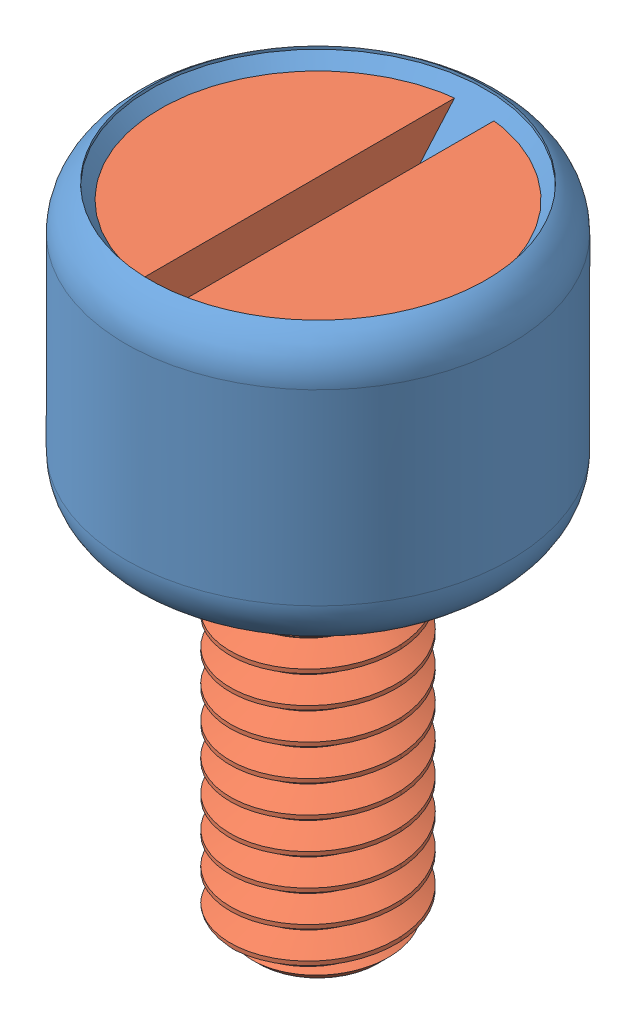
SolidWorks assembly Faux Dzus Stud, configuration Default. Lengths in mm.
Overall size (9.65 16.56 9.65).
2 component instances, 2 part files, 6 mates.
Components (placement in the parent):
- Faux Dzus Stud-1: Faux Dzus Stud [Default] at (0 5.4356 0) x (0 -1 0) z (0 0 1) size (7.05 9.65 9.65)
- 90275A196 - FHS, 82 CSK, 8-32 X .625, STEEL, ZINC-1: 90275A196 - FHS, 82 CSK, 8-32 X .625, STEEL, ZINC [90275A196] at (0 4.1528 0) x (0 0 1) z (0 1 0) size (7.86 7.92 16.2)
Mates (geometry in assembly coordinates):
- Concentric1: concentric aligned: cylinder of Faux Dzus Stud-1 through (0 7.239 0) axis (0 1 0) radius 2.4574
- Coincident1: coincident aligned: plane of Faux Dzus Stud-1 through (0 5.4356 0) normal (1 0 0); plane of assembly through (0 0 0) normal (1 0 0)
- Coincident2: coincident anti-aligned: plane of Faux Dzus Stud-1 through (-4.7498 0 -4.7498) normal (0 -1 0); plane of assembly through (0 0 0) normal (0 1 0)
- Concentric3: concentric aligned: cone of Faux Dzus Stud-1 through (0 6.985 0) axis (0 -1 0); cone of 90275A196 - FHS, 82 CSK, 8-32 X .625, STEEL, ZINC-1 through (0 6.6928 0) axis (0 -1 0)
- Coincident3: coincident aligned: cone of Faux Dzus Stud-1 through (0 6.985 0) axis (0 -1 0); cone of 90275A196 - FHS, 82 CSK, 8-32 X .625, STEEL, ZINC-1 through (0 6.6928 0) axis (0 -1 0)
- Coincident4: coincident aligned: plane of Faux Dzus Stud-1 through (0 5.4356 0) normal (0 0 1); plane of 90275A196 - FHS, 82 CSK, 8-32 X .625, STEEL, ZINC-1 through (0 4.1528 0) normal (0 0 1)
